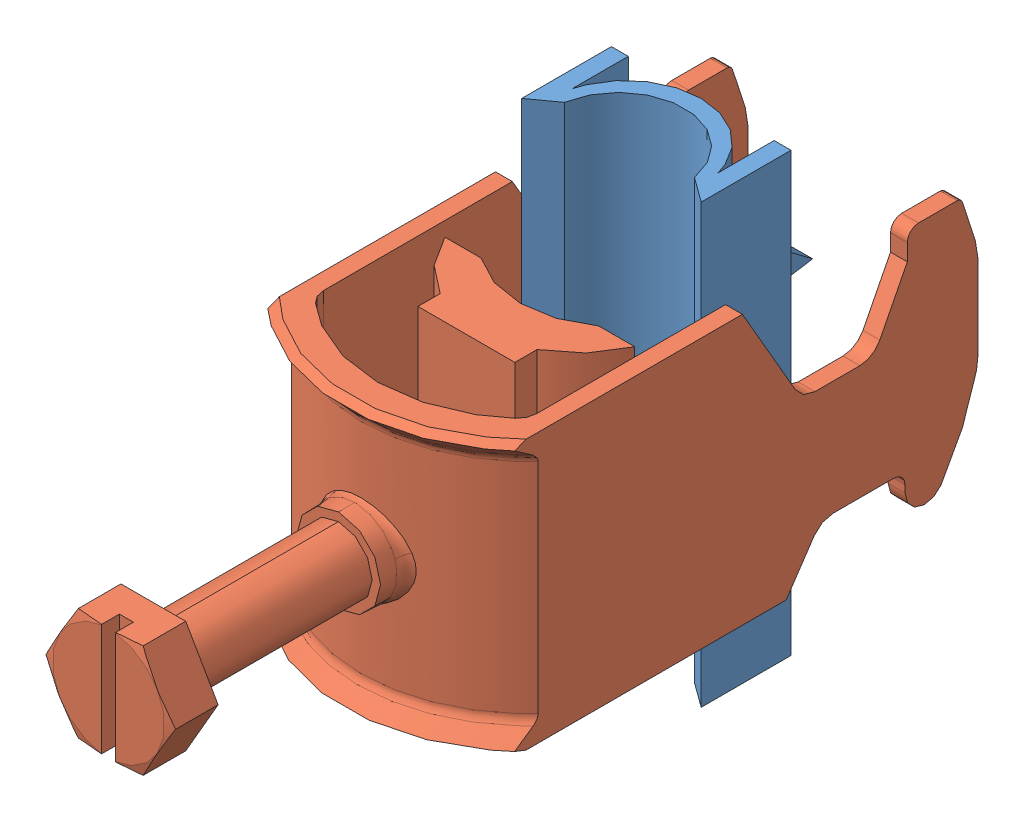
SolidWorks assembly 7078_000, configuration Default. Lengths in mm.
Overall size (22.86 39 66.51).
2 component instances, 2 part files, 6 mates.
Components (placement in the parent):
- 7078_000-counter-1: 7078_000-counter [Default] at (11 12 -52.83) x (-1 0 0) z (0 -1 0) size (16 13.04 39)
- 7078_000-shelle-1: 7078_000-shelle [Default] at (11 12 -20.5) x (-1 0 0) z (0 -1 0) size (22.86 66.51 24)
Mates (geometry in assembly coordinates):
- Konzentrisch1: concentric aligned: cylinder of 7078_000-counter-1 through (-11 -7.5 45.45) axis (0 1 0) radius 5.88; cylinder of 7078_000-shelle-1 through (-11 0.25 45.45) axis (0 1 0) radius 8.75
- Parallel1: parallel anti-aligned: plane of 7078_000-counter-1 through (-19 -7.5 52.83) normal (-1 0 0); plane of 7078_000-shelle-1 through (-20.5 0 66.5) normal (1 0 0)
- Breite1: width anti-aligned: plane of 7078_000-counter-1 through (-11 -7.5 46.105) normal (0 -1 0); plane of 7078_000-counter-1 through (-11 31.5 46.105) normal (0 1 0); plane of 7078_000-shelle-1 through (-11 23.75 41.95) normal (0 1 0); plane of 7078_000-shelle-1 through (-11 0.25 41.95) normal (0 -1 0)
- Deckungsgleich3: coincident anti-aligned: plane of 7078_000-shelle-1 through (0 0 -49.4) normal (0 -1 0); plane of assembly
- Deckungsgleich4: coincident anti-aligned: plane of 7078_000-shelle-1 through (0 16.8 -51.9663) normal (-1 0 0); plane of assembly
- Deckungsgleich5: coincident aligned: plane of 7078_000-shelle-1 through (6 12 0) normal (0 0 1); plane of assembly
